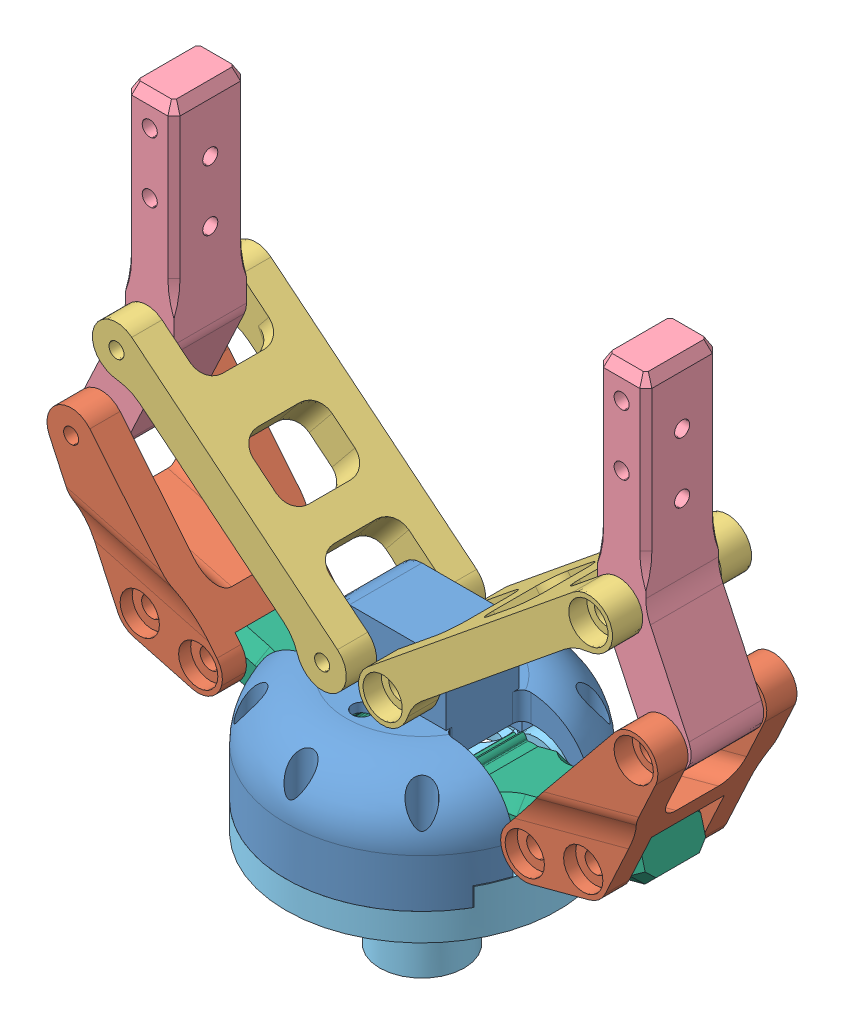
SolidWorks assembly HEBI Robotics-A-2143-02, configuration Default. Lengths in mm.
Overall size (112.08 105.21 45).
10 component instances, 6 part files, 25 mates.
Components (placement in the parent):
- HEBI Robotics-A-2143-02_PM-2357-02-1: HEBI Robotics-A-2143-02_PM-2357-02 [Default] at (0 30.9247 0) x (0 0 -1) z (1 0 0) size (45 28 44.67)
- HEBI Robotics-A-2143-02_PM-2358-02-1: HEBI Robotics-A-2143-02_PM-2358-02 [Default] at (-31.436 29.5333 0) x (0 0 -1) z (0.966127 -0.258068 0) size (23 26 33)
- HEBI Robotics-A-2143-02_PM-2358-02-2: HEBI Robotics-A-2143-02_PM-2358-02 [Default] at (31.4354 29.5354 0) x (0 0 1) z (-0.966125 -0.258076 0) size (23 26 33)
- HEBI Robotics-A-2143-02_PM-2359-02-1: HEBI Robotics-A-2143-02_PM-2359-02 [Default] at (21.9996 52.7813 0) x (0 0 1) z (0.775123 0.631811 0) size (23 8 51.86)
- HEBI Robotics-A-2143-02_PM-2359-02-2: HEBI Robotics-A-2143-02_PM-2359-02 [Default] at (-22.0004 52.7803 0) x (0 0 -1) z (-0.775159 0.631767 0) size (23 8 51.86)
- HEBI Robotics-A-2143-02_PM-2360-02-1: HEBI Robotics-A-2143-02_PM-2360-02 [Default] at (-39.0008 66.6359 0) x (-1 -0.000025 0) z (0 0 -1) size (15.5 54 12.08)
- HEBI Robotics-A-2143-02_PM-2360-02-2: HEBI Robotics-A-2143-02_PM-2360-02 [Default] at (38.9992 66.6378 0) x (1 0.000025 0) z (0 0 1) size (15.5 54 12.08)
- HEBI Robotics-A-2055-01_PM-2218-01-1: HEBI Robotics-A-2055-01_PM-2218-01 [Default] at (0 11.4247 0) size (45 32.5 45)
- HEBI Robotics-A-2055-01_PM-2221-01-1: HEBI Robotics-A-2055-01_PM-2221-01 [Default] at (12.5 22.9247 0) x (0.966125 0.258076 0) z (0 0 1) size (35.49 9.86 12)
- HEBI Robotics-A-2055-01_PM-2221-01-2: HEBI Robotics-A-2055-01_PM-2221-01 [Default] at (-12.5 22.9247 0) x (-0.966162 0.257934 0) z (0 0 -1) size (35.49 9.86 12)
Mates (geometry in assembly coordinates):
- Coincident19: coincident anti-aligned: plane of HEBI Robotics-A-2143-02_PM-2357-02-1 through (0 30.9247 0) normal (0 0 -1); plane of HEBI Robotics-A-2143-02_PM-2359-02-1 through (21.9996 52.7813 0) normal (0 0 1)
- Coincident20: coincident aligned: plane of HEBI Robotics-A-2143-02_PM-2357-02-1 through (0 30.9247 0) normal (0 0 -1); plane of HEBI Robotics-A-2143-02_PM-2359-02-2 through (-22.0004 52.7803 0) normal (0 0 -1)
- Concentric3: concentric aligned: cylinder of HEBI Robotics-A-2143-02_PM-2357-02-1 through (5 38.9247 6) axis (0 0 1) radius 2.75; cylinder of HEBI Robotics-A-2143-02_PM-2359-02-1 through (5 38.9247 11.5) axis (0 0 1) radius 3.25
- Concentric4: concentric anti-aligned: cylinder of HEBI Robotics-A-2143-02_PM-2357-02-1 through (-5 38.9247 6) axis (0 0 1) radius 2.75; cylinder of HEBI Robotics-A-2143-02_PM-2359-02-2 through (-5 38.9247 6.5) axis (0 0 -1) radius 1.25
- Coincident21: coincident anti-aligned: plane of HEBI Robotics-A-2143-02_PM-2357-02-1 through (0 30.9247 0) normal (0 0 -1); plane of HEBI Robotics-A-2143-02_PM-2360-02-2 through (38.9992 66.6378 0) normal (0 0 1)
- Coincident22: coincident aligned: plane of HEBI Robotics-A-2143-02_PM-2357-02-1 through (0 30.9247 0) normal (0 0 -1); plane of HEBI Robotics-A-2143-02_PM-2360-02-1 through (-39.0008 66.6359 0) normal (0 0 -1)
- Concentric5: concentric aligned: cylinder of HEBI Robotics-A-2143-02_PM-2359-02-1 through (38.9992 66.6378 -6.5) axis (0 0 1) radius 1.25; cylinder of HEBI Robotics-A-2143-02_PM-2360-02-2 through (38.9992 66.6378 6) axis (0 0 1) radius 2.75
- Concentric6: concentric aligned: cylinder of HEBI Robotics-A-2143-02_PM-2359-02-2 through (-39.0008 66.6359 -11.5) axis (0 0 -1) radius 3.25; cylinder of HEBI Robotics-A-2143-02_PM-2360-02-1 through (-39.0008 66.6359 -6) axis (0 0 -1) radius 2.75
- Coincident23: coincident anti-aligned: plane of HEBI Robotics-A-2143-02_PM-2357-02-1 through (0 30.9247 0) normal (0 0 -1); plane of HEBI Robotics-A-2143-02_PM-2358-02-2 through (31.4354 29.5354 0) normal (0 0 1)
- Coincident24: coincident aligned: plane of HEBI Robotics-A-2143-02_PM-2357-02-1 through (0 30.9247 0) normal (0 0 -1); plane of HEBI Robotics-A-2143-02_PM-2358-02-1 through (-31.436 29.5333 0) normal (0 0 -1)
- Concentric8: concentric aligned: cylinder of HEBI Robotics-A-2143-02_PM-2358-02-2 through (46.4996 50.638 -6.5) axis (0 0 1) radius 1.25; cylinder of HEBI Robotics-A-2143-02_PM-2360-02-2 through (46.4996 50.638 6) axis (0 0 1) radius 2.75
- Concentric9: concentric aligned: cylinder of HEBI Robotics-A-2143-02_PM-2358-02-1 through (-46.5004 50.6357 6.5) axis (0 0 -1) radius 1.25; cylinder of HEBI Robotics-A-2143-02_PM-2360-02-1 through (-46.5004 50.6357 -6) axis (0 0 -1) radius 2.75
- Coincident25: coincident anti-aligned: plane of HEBI Robotics-A-2143-02_PM-2357-02-1 through (0 15.9247 0) normal (0 -1 0); plane of HEBI Robotics-A-2055-01_PM-2218-01-1 through (0 15.9247 0) normal (0 1 0)
- Concentric10: concentric anti-aligned: cylinder of HEBI Robotics-A-2055-01_PM-2218-01-1 through (12.5 22.9247 11) axis (0 0 1) radius 2.015; cylinder of HEBI Robotics-A-2055-01_PM-2221-01-1 through (12.5 22.9247 -6) axis (0 0 -1) radius 2.775
- Width1: width anti-aligned: plane of HEBI Robotics-A-2055-01_PM-2221-01-1 through (12.5 22.9247 -6) normal (0 0 -1); plane of HEBI Robotics-A-2055-01_PM-2218-01-1 through (12.5 22.9247 6) normal (0 0 1); plane of HEBI Robotics-A-2055-01_PM-2221-01-1 through (12.5 22.9247 11) normal (0 0 1); plane of HEBI Robotics-A-2055-01_PM-2218-01-1 through (12.5 22.9247 -11) normal (0 0 -1)
- Concentric11: concentric aligned: cylinder of HEBI Robotics-A-2055-01_PM-2218-01-1 through (-12.5 22.9247 11) axis (0 0 1) radius 2.015; cylinder of HEBI Robotics-A-2055-01_PM-2221-01-2 through (-12.5 22.9247 6) axis (0 0 1) radius 2.775
- Width2: width aligned: plane of HEBI Robotics-A-2055-01_PM-2221-01-2 through (-12.5 22.9247 -6) normal (0 0 -1); plane of HEBI Robotics-A-2055-01_PM-2218-01-1 through (-12.5 22.9247 6) normal (0 0 1); plane of HEBI Robotics-A-2055-01_PM-2221-01-2 through (-12.5 22.9247 -11) normal (0 0 -1); plane of HEBI Robotics-A-2055-01_PM-2218-01-1 through (-12.5 22.9247 11) normal (0 0 1)
- Coincident26: coincident anti-aligned: plane of HEBI Robotics-A-2143-02_PM-2357-02-1 through (0 30.9247 0) normal (0 0 -1); plane of HEBI Robotics-A-2055-01_PM-2218-01-1 through (0 11.4247 0) normal (0 0 1)
- Coincident27: coincident aligned: plane of HEBI Robotics-A-2143-02_PM-2357-02-1 through (0 30.9247 0) normal (1 0 0); plane of HEBI Robotics-A-2055-01_PM-2218-01-1 through (0 11.4247 0) normal (1 0 0)
- Concentric12: concentric anti-aligned: cylinder of HEBI Robotics-A-2143-02_PM-2358-02-1 through (-26.9924 26.7937 -10) axis (0 0 -1) radius 3.25; cylinder of HEBI Robotics-A-2055-01_PM-2221-01-2 through (-26.9924 26.7937 6) axis (0 0 1) radius 1.25
- Concentric13: concentric aligned: cylinder of HEBI Robotics-A-2143-02_PM-2358-02-2 through (36.6531 29.3766 -10) axis (0 0 -1) radius 3.25; cylinder of HEBI Robotics-A-2055-01_PM-2221-01-1 through (36.6531 29.3766 -6) axis (0 0 -1) radius 1.25
- Parallel1: parallel anti-aligned: plane of HEBI Robotics-A-2143-02_PM-2360-02-1 through (-35.0008 66.636 -6) normal (1 0.000025 0); plane of HEBI Robotics-A-2143-02_PM-2360-02-2 through (34.9992 66.6377 6) normal (-1 -0.000025 0)
- Coincident29: coincident aligned: plane of HEBI Robotics-A-2143-02_PM-2360-02-1 through (-35.0016 100.636 -6) normal (-0.000025 1 0); plane of HEBI Robotics-A-2143-02_PM-2360-02-2 through (34.9984 100.6377 6) normal (-0.000025 1 0)
- Concentric14: concentric aligned: cylinder of HEBI Robotics-A-2143-02_PM-2358-02-2 through (26.9919 26.7959 -10) axis (0 0 -1) radius 3.25; cylinder of HEBI Robotics-A-2055-01_PM-2221-01-1 through (26.9919 26.7959 -6) axis (0 0 -1) radius 1.25
- Distance1: distance = 70 mm anti-aligned: plane of HEBI Robotics-A-2143-02_PM-2360-02-2 through (34.9992 66.6377 6) normal (-1 -0.000025 0); plane of HEBI Robotics-A-2143-02_PM-2360-02-1 through (-35.0008 66.636 -6) normal (1 0.000025 0)
